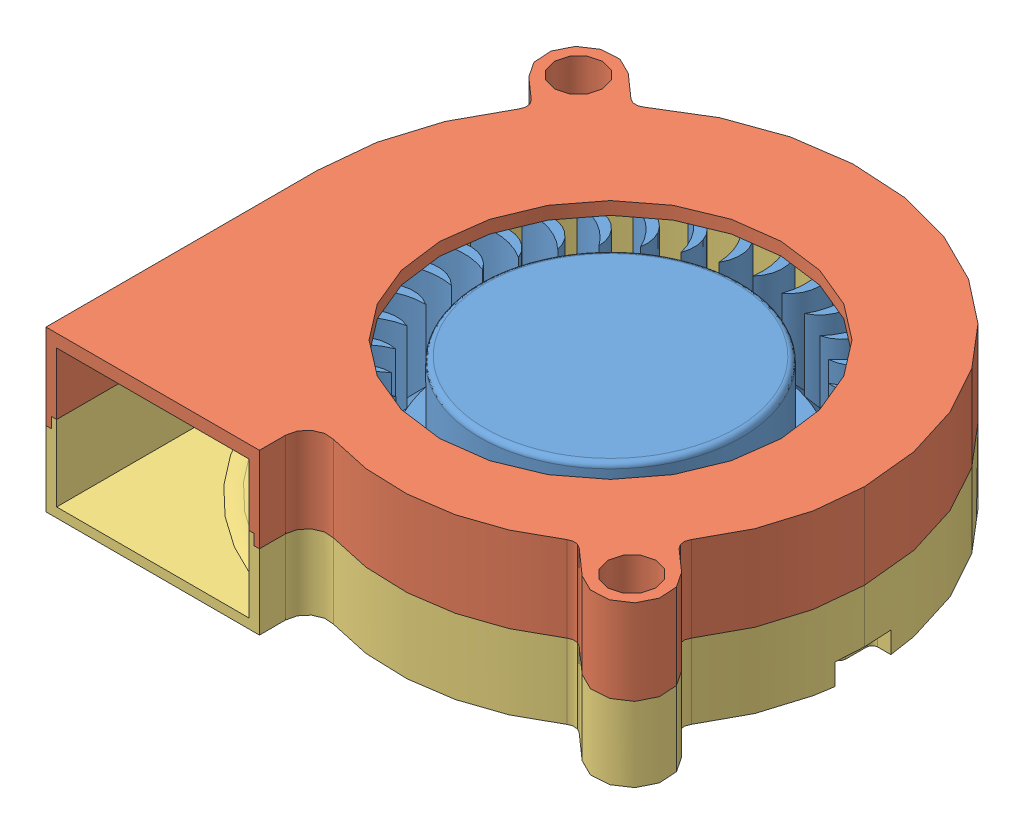
SolidWorks assembly Radial-Cooling-Fan-5015-DC12V, configuration По умолчанию. Lengths in mm.
Overall size (51.3 15 51.07).
3 component instances, 3 part files, 5 mates.
Components (placement in the parent):
- turbine-1: turbine [По умолчанию] at (0 3.2 0) x (0.990476 0 -0.137682) z (0.137682 0 0.990476) size (38.96 10.5 38.91)
- top-3: top [По умолчанию] at (0 15 0) size (51.3 8 51.07)
- bottom-1: bottom [По умолчанию] at origin size (51.3 8.5 51.07)
Mates (geometry in assembly coordinates):
- Совпадение5: coordinate: point of bottom-1
- Совпадение6: coincident anti-aligned: line of top-3 through (-27.5 7 25.4) axis (0 1 0); line of bottom-1 through (-27.5 7 25.4) axis (0 -1 0)
- Совпадение7: coincident anti-aligned: plane of top-3 through (-23 7 -20) normal (0 -1 0); plane of bottom-1 through (-1.85 7 -0.1334) normal (0 1 0)
- Концентричный2: concentric aligned: cylinder of turbine-1 through (0 12.9 0) axis (0 -1 0) radius 11.4; cylinder of bottom-1 through (0 8 0) axis (0 -1 0) radius 2.5
- Расстояние1: distance = 2 mm anti-aligned: plane of turbine-1 through (0 3.2 0) normal (0 -1 0); plane of bottom-1 through (-23 1.2 -20) normal (0 1 0)
